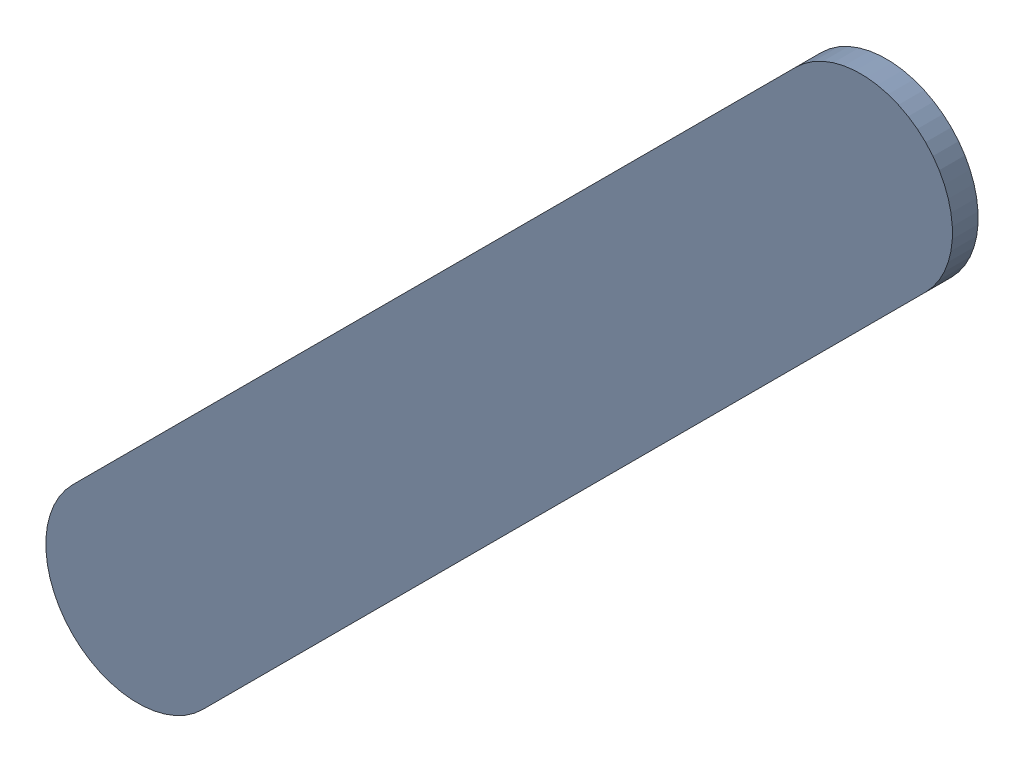
SolidWorks assembly Track (25.1mm,47.6mm)(26.1mm,48.6mm) on Bottom Layer, configuration Predeterminado. Lengths in mm.
Overall size (1.25 1.25 0.04).
2 component instances, 1 part files, 0 mates.
Components (placement in the parent):
- Track (25.1mm,47.6mm)(26.1mm,48.6mm) on Bottom Layer-1-1: Track (25.1mm,47.6mm)(26.1mm,48.6mm) on Bottom Layer-1 [Predeterminado] at (-68.317 -44.187 -0.4013) size (1.25 1.25 0.04)
  - Track (25.1mm,47.6mm)(26.1mm,48.6mm) on Bottom Layer-Part-1-1: Track (25.1mm,47.6mm)(26.1mm,48.6mm) on Bottom Layer-Part-1 [Predeterminado] at origin size (1.25 1.25 0.04)
